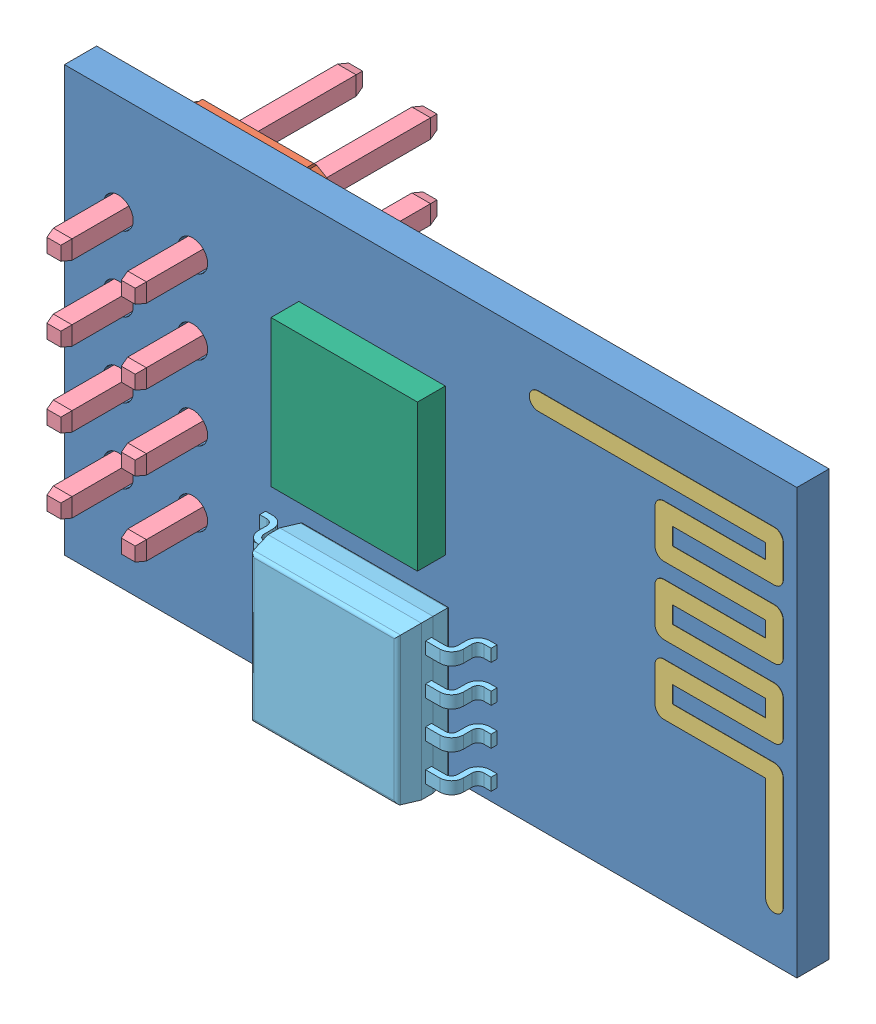
SolidWorks assembly ESP01 v1, configuration Valor predeterminado. Lengths in mm.
Overall size (25 14.5 10.3).
14 component instances, 6 part files, 0 mates.
Components (placement in the parent):
- ESP01 v1(2)-1: ESP01 v1(2) [Valor predeterminado] at origin size (25 14.5 10.3)
  - Platine-1: Platine [Valor predeterminado] at origin size (25 14.5 1.1)
  - PinSockel-1: PinSockel [Valor predeterminado] at (1.8391 11.06 0) x (1 0 0) z (0 0 -1) size (5 10.16 2.5)
  - PCB_Antenna-1: PCB_Antenna [Valor predeterminado] at (1 16 0.81) x (0 -1 0) z (-1 0 0) size (11.4 0.04 8.66)
  - Pin_Stiftleiste-1: Pin_Stiftleiste [Valor predeterminado] at (1.8391 3.44 0) x (-1 0 0) z (0 0 -1) size (0.64 0.64 10.3)
  - Pin_Stiftleiste-2: Pin_Stiftleiste [Valor predeterminado] at (4.3791 3.44 0) x (-1 0 0) z (0 0 -1) size (0.64 0.64 10.3)
  - Pin_Stiftleiste-3: Pin_Stiftleiste [Valor predeterminado] at (1.8391 5.98 0) x (-1 0 0) z (0 0 -1) size (0.64 0.64 10.3)
  - Pin_Stiftleiste-4: Pin_Stiftleiste [Valor predeterminado] at (4.3791 5.98 0) x (-1 0 0) z (0 0 -1) size (0.64 0.64 10.3)
  - Pin_Stiftleiste-5: Pin_Stiftleiste [Valor predeterminado] at (1.8391 8.52 0) x (-1 0 0) z (0 0 -1) size (0.64 0.64 10.3)
  - Pin_Stiftleiste-6: Pin_Stiftleiste [Valor predeterminado] at (4.3791 8.52 0) x (-1 0 0) z (0 0 -1) size (0.64 0.64 10.3)
  - Pin_Stiftleiste-7: Pin_Stiftleiste [Valor predeterminado] at (1.8391 11.06 0) x (-1 0 0) z (0 0 -1) size (0.64 0.64 10.3)
  - Pin_Stiftleiste-8: Pin_Stiftleiste [Valor predeterminado] at (4.3791 11.06 0) x (-1 0 0) z (0 0 -1) size (0.64 0.64 10.3)
  - SerialFlashMem-1: SerialFlashMem [Valor predeterminado] at (8.2 0.1 1.1) size (7.9 5.23 1.95)
  - ESP8266EX-1: ESP8266EX [Valor predeterminado] at (8 6.5 1.1) size (5 5 0.95)
